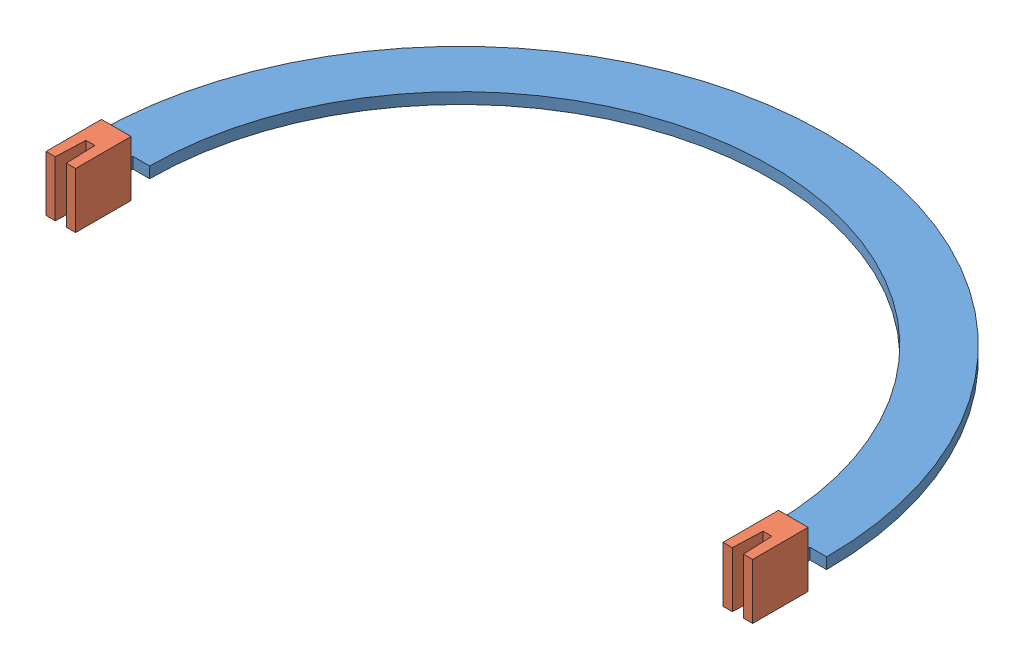
SolidWorks assembly spacer, configuration Default. Lengths in mm.
Overall size (198 15 115.5).
3 component instances, 2 part files, 7 mates.
Components (placement in the parent):
- spacer-main-1: spacer-main [Default] at origin size (198 3 104)
- spacer-fix-1: spacer-fix [Default] at (-91.5 -0.1 11.5) x (0 -1 0) z (1 0 0) size (15 15 8)
- spacer-fix-2: spacer-fix [Default] at (91.5 -0.1 11.5) x (0 -1 0) z (1 0 0) size (15 15 8)
Mates (geometry in assembly coordinates):
- Coincident1: coordinate: point of spacer-main-1
- Coincident4: coincident anti-aligned: plane of spacer-main-1 through (-88.5 1.5 0) normal (1 0 0); plane of spacer-fix-1 through (-88.5 -1.7 1.5) normal (-1 0 0)
- Coincident5: coincident anti-aligned: plane of spacer-main-1 through (0 1.5 -5) normal (0 1 0); plane of spacer-fix-1 through (-94.5 1.5 1.5) normal (0 -1 0)
- Coincident6: coincident anti-aligned: line of spacer-main-1 through (6 -94.5 1.5) axis (0 1 0); line of spacer-fix-1 through (6 -88.5 1.5) axis (0 -1 0)
- Coincident7: coincident: plane of spacer-main-1 through (0 1.5 -5) normal (0 1 0); plane of spacer-fix-2 through (88.5 1.5 17.7348) normal (0 -1 0)
- Coincident8: coincident: plane of spacer-main-1 through (88.5 1.5 -5) normal (-1 0 0); plane of spacer-fix-2 through (88.5 -1.7 17.7348) normal (1 0 0)
- Coincident10: coincident anti-aligned: line of spacer-main-1 through (6 88.5 1.5) axis (0 1 0); line of spacer-fix-2 through (94.5 1.5 16.2348) axis (-1 0 0)
